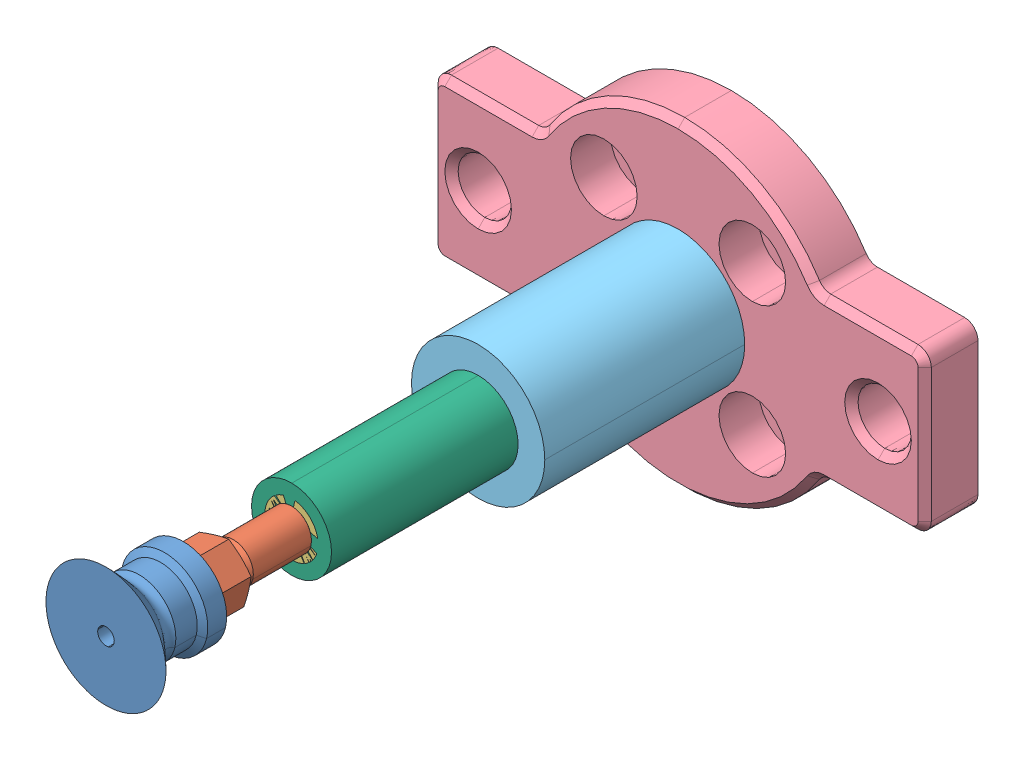
SolidWorks assembly 吸盘夹具, configuration 默认. Lengths in mm.
Overall size (74 53.08 114.36).
10 component instances, 7 part files, 0 mates.
Components (placement in the parent):
- 吸盘夹具.STEP-1: 吸盘夹具.STEP [默认] at origin size (74 53.08 114.36)
  - ZPT16UN-A6.STEP-1: ZPT16UN-A6.STEP [默认] at (-2.0377 6.0452 150.5502) x (0.235175 0.971953 0) z (-0.971953 0.235175 0) size (18 43.5 18)
    - _ZP16U_T.STEP-1: _ZP16U_T.STEP [默认] at origin size (18 12.5 18)
    - _ZPT2-A6_10_16.STEP-1: _ZPT2-A6_10_16.STEP [默认] at (0 12.5 0) size (9.24 31 8)
    - _ZPT2-A6_10_16_NUT.STEP-1: _ZPT2-A6_10_16_NUT.STEP [默认] at (0 27.84 0) size (9.24 3 8)
    - _ZPT2-A6_10_16_NUT.STEP-2: _ZPT2-A6_10_16_NUT.STEP [默认] at (0 30.84 0) size (9.24 3 8)
  - OX-03AI.STEP-1: OX-03AI.STEP [默认] at (-2.0377 6.0452 -69.2898)
  - ______________.STEP-1: ______________.STEP [默认] at (-2.0377 6.0452 56.7102) x (1 0 0) z (0 -1 0) size (74 8 48)
  - ____________.STEP-1: ____________.STEP [默认] at (-2.0377 6.0452 94.7102) x (0 1 0) z (-1 0 0) size (20 30 20)
  - __________.STEP-1: __________.STEP [默认] at (-2.0377 6.0452 122.7102) x (0.007086 0.999975 0) z (0 0 -1) size (12 12 36)
